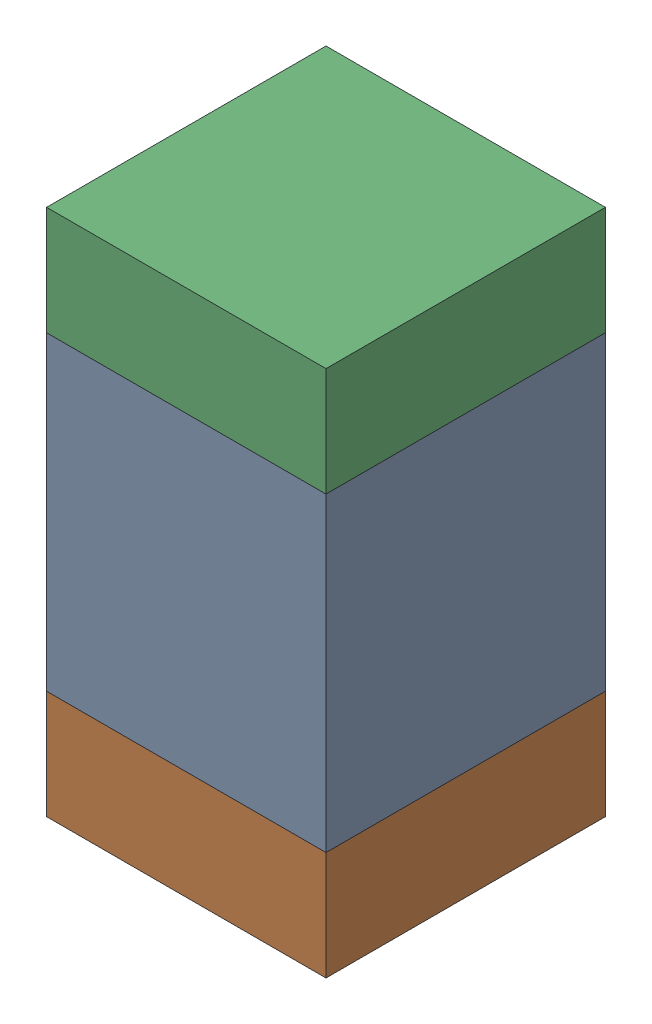
SolidWorks assembly C2, configuration Default. Lengths in mm.
Overall size (0.9 1.7 0.9).
6 component instances, 2 part files, 0 mates.
Components (placement in the parent):
- 5613956208-1: 5613956208 [Default] at (136.5 102.9 -2.5914) size (0.9 1 0.9)
  - Extruded_2-1: Extruded_2 [Default] at origin size (0.9 1 0.9)
- 5613953728-1: 5613953728 [Default] at (136.5 102.225 -2.5914) size (0.9 0.35 0.9)
  - Extruded_8-1: Extruded_8 [Default] at origin size (0.9 0.35 0.9)
- 5613953728-2: 5613953728 [Default] at (136.5 103.575 -2.5914) size (0.9 0.35 0.9)
  - Extruded_8-1: Extruded_8 [Default] at origin size (0.9 0.35 0.9)
